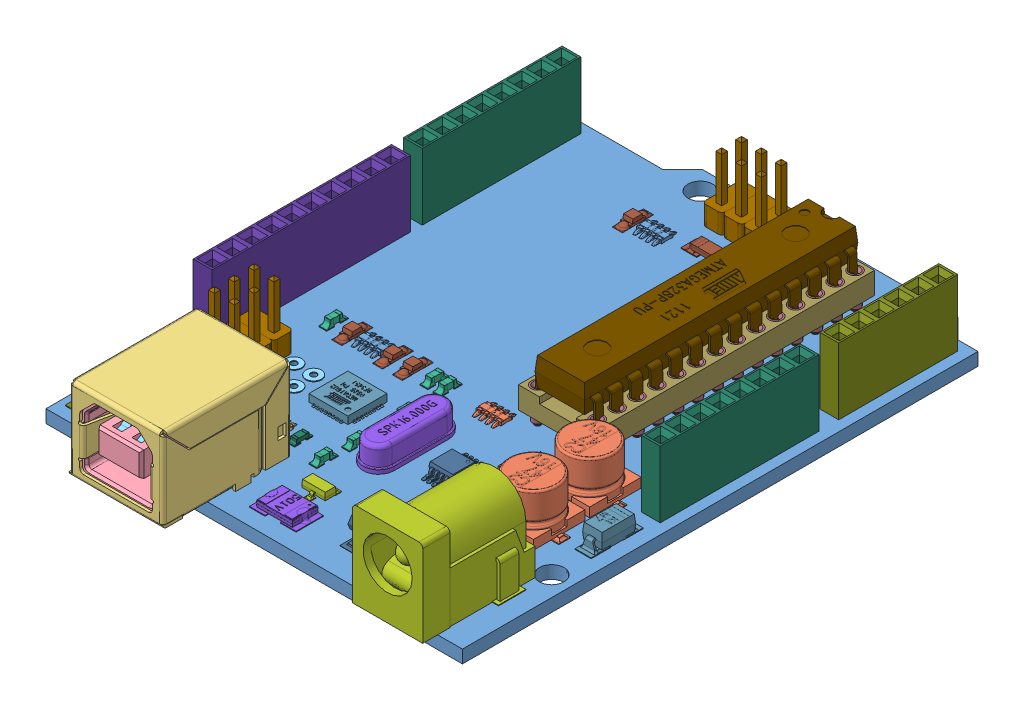
SolidWorks assembly arduino uno, configuration Default. Lengths in mm.
Overall size (53.34 15.25 74.93).
88 component instances, 35 part files, 136 mates.
Components (placement in the parent):
- unoboard blue-1: unoboard blue [Default] at origin size (53.34 1.65 68.58)
- 47uf CAP Dcase-1: 47uf CAP Dcase [Default] at (-9.4141 0 -18.4991) x (0 0 -1) z (1 0 0) size (6.6 5.81 8)
- USB type b-1: USB type b [Default] at (-38.02 0.43 6.35) size (14.34 15.2 16.5)
  - USB SHELL-1: USB SHELL [Default] at origin size (14.34 15.2 16.5)
  - USB core-1: USB core [Default] at origin size (11.3 10.68 15.75)
  - usb top contact-1: usb top contact [Default] at (1.25 6.09 -0.38) size (1 9.67 13.76)
  - usb btm contact-1: usb btm contact [Default] at (1.25 4.41 -0.38) size (1 6.84 11.76)
  - usb btm contact-2: usb btm contact [Default] at (-1.25 4.41 -0.38) size (1 6.84 11.76)
  - usb top contact-2: usb top contact [Default] at (-1.25 6.09 -0.38) size (1 9.67 13.76)
- power jack-1: power jack [Default] at (-7.675 0 1.905) size (11.2 15.2 15.9)
- 47uf CAP Dcase-2: 47uf CAP Dcase [Default] at (-9.4141 0 -25.7132) x (0 0 -1) z (1 0 0) size (6.6 5.81 8)
- crystal-1: crystal [Default] at (-26.162 0 -18.923) x (1 0 0) z (0 0 -1) size (4 5 11)
- 2pin_header__02-1: 2pin_header__02 [Default] at (-46.23 0 -15.75) size (5 11.75 2.54)
- nano - reg-1: nano - reg [Default] at (-17.399 0 -7.747) size (6.5 1.69 8.3)
- led-1: led [Default] at (-34.29 0 -27.94) x (0 0 1) z (-1 0 0) size (4 0.86 1.35)
- 2pin_header__02-2: 2pin_header__02 [Default] at (-30.43 0 -64.91) x (0 0 1) z (-1 0 0) size (5 11.75 2.54)
- dip28-1: dip28 [Default] at (-16.383 1.5 -46.355) x (0 0 -1) z (1 0 0) size (35.48 7.37 10.1)
  - dip28-1: dip28 [Default] at origin size (35.48 2.8 10.1)
  - dip socket pin-1: dip socket pin [Default] at (16.51 2.8 -3.81) size (1.7 7.37 1.7)
  - dip socket pin-2: dip socket pin [Default] at (16.51 2.8 3.81) size (1.7 7.37 1.7)
  - dip socket pin-3: dip socket pin [Default] at (13.97 2.8 -3.81) size (1.7 7.37 1.7)
  - dip socket pin-4: dip socket pin [Default] at (13.97 2.8 3.81) size (1.7 7.37 1.7)
  - dip socket pin-5: dip socket pin [Default] at (11.43 2.8 -3.81) size (1.7 7.37 1.7)
  - dip socket pin-6: dip socket pin [Default] at (11.43 2.8 3.81) size (1.7 7.37 1.7)
  - dip socket pin-7: dip socket pin [Default] at (8.89 2.8 -3.81) size (1.7 7.37 1.7)
  - dip socket pin-8: dip socket pin [Default] at (8.89 2.8 3.81) size (1.7 7.37 1.7)
  - dip socket pin-9: dip socket pin [Default] at (6.35 2.8 -3.81) size (1.7 7.37 1.7)
  - dip socket pin-10: dip socket pin [Default] at (6.35 2.8 3.81) size (1.7 7.37 1.7)
  - dip socket pin-11: dip socket pin [Default] at (3.81 2.8 -3.81) size (1.7 7.37 1.7)
  - dip socket pin-12: dip socket pin [Default] at (3.81 2.8 3.81) size (1.7 7.37 1.7)
  - dip socket pin-13: dip socket pin [Default] at (1.27 2.8 -3.81) size (1.7 7.37 1.7)
  - dip socket pin-14: dip socket pin [Default] at (1.27 2.8 3.81) size (1.7 7.37 1.7)
  - dip socket pin-15: dip socket pin [Default] at (-1.27 2.8 -3.81) size (1.7 7.37 1.7)
  - dip socket pin-16: dip socket pin [Default] at (-1.27 2.8 3.81) size (1.7 7.37 1.7)
  - dip socket pin-17: dip socket pin [Default] at (-3.81 2.8 -3.81) size (1.7 7.37 1.7)
  - dip socket pin-18: dip socket pin [Default] at (-3.81 2.8 3.81) size (1.7 7.37 1.7)
  - dip socket pin-19: dip socket pin [Default] at (-6.35 2.8 -3.81) size (1.7 7.37 1.7)
  - dip socket pin-20: dip socket pin [Default] at (-6.35 2.8 3.81) size (1.7 7.37 1.7)
  - dip socket pin-21: dip socket pin [Default] at (-8.89 2.8 -3.81) size (1.7 7.37 1.7)
  - dip socket pin-22: dip socket pin [Default] at (-8.89 2.8 3.81) size (1.7 7.37 1.7)
  - dip socket pin-23: dip socket pin [Default] at (-11.43 2.8 -3.81) size (1.7 7.37 1.7)
  - dip socket pin-24: dip socket pin [Default] at (-11.43 2.8 3.81) size (1.7 7.37 1.7)
  - dip socket pin-25: dip socket pin [Default] at (-13.97 2.8 -3.81) size (1.7 7.37 1.7)
  - dip socket pin-26: dip socket pin [Default] at (-13.97 2.8 3.81) size (1.7 7.37 1.7)
  - dip socket pin-27: dip socket pin [Default] at (-16.51 2.8 -3.81) size (1.7 7.37 1.7)
  - dip socket pin-28: dip socket pin [Default] at (-16.51 2.8 3.81) size (1.7 7.37 1.7)
- 2pin_header__02-3: 2pin_header__02 [Default] at (-27.89 0 -64.91) x (0 0 1) z (-1 0 0) size (5 11.75 2.54)
- 2pin_header__02-4: 2pin_header__02 [Default] at (-25.35 0 -64.91) x (0 0 1) z (-1 0 0) size (5 11.75 2.54)
- 2pin_header__02-5: 2pin_header__02 [Default] at (-46.23 0 -18.29) size (5 11.75 2.54)
- 2pin_header__02-6: 2pin_header__02 [Default] at (-46.23 0 -20.83) size (5 11.75 2.54)
- atmega16u2-1: atmega16u2 [Default] at (-34.671 0.06 -20) x (1 0 0) z (0 0 -1) size (5.5 1.01 5.5)
- led-2: led [Default] at (-36.83 0 -27.94) x (0 0 1) z (-1 0 0) size (4 0.86 1.35)
- led-3: led [Default] at (-42.037 0 -27.94) x (0 0 1) z (-1 0 0) size (4 0.86 1.35)
- led-4: led [Default] at (-36.576 0 -58.42) x (0 0 1) z (-1 0 0) size (4 0.86 1.35)
- 8 PORT HEADER-3: 8 PORT HEADER [Default] at (-50.8 0 -45.72) x (0 0 -1) z (1 0 0) size (20.32 10.51 2.41)
- 8 PORT HEADER-4: 8 PORT HEADER [Default] at (-2.54 0 -27.94) x (0 0 -1) z (1 0 0) size (20.32 10.51 2.41)
- 6 PORT HEADER-3: 6 PORT HEADER [Default] at (-2.54 0 -50.8) x (0 0 -1) z (1 0 0) size (15.24 10.51 2.41)
- 10 PORT HEADER-1: 10 PORT HEADER [Default] at (-50.8 0 -18.796) x (0 0 -1) z (1 0 0) size (25.4 10.51 2.41)
- ATMEL328P-1: ATMEL328P [Default] at (-16.383 4.3 -46.355) x (0 0 -1) z (1 0 0) size (35 7.27 7.87)
- 102 RESISTOR PACK-1: 102 RESISTOR PACK [Default] at (-33.782 0 -58.42) size (3.2 0.46 3)
- 102 RESISTOR PACK-2: 102 RESISTOR PACK [Default] at (-39.37 0 -27.94) size (3.2 0.46 3)
- 103 RESISTOR PACK-3: 103 RESISTOR PACK [Default] at (-23.876 0 -27.94) size (3.2 0.46 3)
- 220 RESISTOR PACK-1: 220 RESISTOR PACK [Default] at (-36.83 0 -12.827) size (3.2 0.46 3)
- 16mhz crystal - measured-1: 16mhz crystal - measured [Default] at (-24.892 0 -41.275) x (0 0 -1) z (1 0 0) size (3.4 0.8 2)
- PADS001-1: PADS001 [Default] at (-39.878 0.1 -18.288) x (-1 0 0) z (0 0 1) size (4.54 0.1 4.54)
- 603 cap on pad-1: 603 cap on pad [Default] at (-44.45 0 -27.94) x (0 0 -1) z (1 0 0) size (2.76 0.9 1.12)
- ssot3-1: ssot3 [Default] at (-26.5 0 -8.128) x (-1 0 0) z (0 0 -1) size (3 1.13 3.09)
- mf-msmf050-2-1: mf-msmf050-2 [Default] at (-26.5 0 -4.064) size (5.77 1.02 3.72)
- 603 cap on pad-2: 603 cap on pad [Default] at (-29.845 0 -27.94) x (0 0 -1) z (1 0 0) size (2.76 0.9 1.12)
- 603 cap on pad-3: 603 cap on pad [Default] at (-31.496 0 -27.94) x (0 0 -1) z (1 0 0) size (2.76 0.9 1.12)
- lmv358-1: lmv358 [Default] at (-15.24 0 -21.971) x (0 0 -1) z (1 0 0) size (3.7 1.4 2.9)
- 603 cap on pad-4: 603 cap on pad [Default] at (-15.24 0 -18.415) size (2.76 0.9 1.12)
- 603 cap on pad-5: 603 cap on pad [Default] at (-29.845 0 -12.065) x (0 0 1) z (-1 0 0) size (2.76 0.9 1.12)
- 603 cap on pad-6: 603 cap on pad [Default] at (-29.591 0 -22.352) x (0 0 1) z (-1 0 0) size (2.76 0.9 1.12)
- 603 cap on pad-7: 603 cap on pad [Default] at (-29.591 0 -16.002) x (0 0 1) z (-1 0 0) size (2.76 0.9 1.12)
- 603 cap on pad-8: 603 cap on pad [Default] at (-41.91 0 -12.7) x (0 0 1) z (-1 0 0) size (2.76 0.9 1.12)
- lp2985dgkr-1: lp2985dgkr [Default] at (-20.32 0 -19.05) x (0 0 -1) z (1 0 0) size (5.85 1.1 3)
- cd1206 diode-1: cd1206 diode [Default] at (-27.94 0 -59.436) x (0 0 -1) z (1 0 0) size (2.07 0.96 5)
- cd1206 diode-2: cd1206 diode [Default] at (-46.228 0 -13.081) x (0 0 1) z (-1 0 0) size (2.07 0.96 5)
- 603 resistor-1: 603 resistor [Default] at (-29.591 0 -19.05) x (0 0 1) z (-1 0 0) size (2.36 0.61 1.03)
- blm21-1: blm21 [Default] at (-45.085 0 -7.62) x (0 0 -1) z (1 0 0) size (2.76 0.95 1.32)
- m7 diode-1: m7 diode [Default] at (-2.794 0 -21.59) x (0 0 -1) z (1 0 0) size (6.66 2.35 2.5)
- MLC0603-1: MLC0603 [Default] at (-33.655 0 -12.827) x (0 0 -1) z (1 0 0) size (2.36 0.6 1.03)
- MLC0603-2: MLC0603 [Default] at (-39.37 0 -12.827) x (0 0 -1) z (1 0 0) size (2.36 0.6 1.03)
- RESET BUTTON-1: RESET BUTTON [Default] at (-49.403 0 -6.35) size (6.2 3.1 9.6)
  - RESET CORE-1: RESET CORE [Default] at (0 0.1 0) x (-1 0 0) z (0 0 -1) size (6.2 3.1 9.6)
  - RESET-1: RESET [Default] at (0 0.1 0) x (0 0 1) z (-1 0 0) size (7.3 2 6.2)
- 603 cap on pad-9: 603 cap on pad [Default] at (-15.24 0 -25.625) size (2.76 0.9 1.12)
Mates (geometry in assembly coordinates):
- Distance1: distance = 1.905 mm aligned: plane of power jack-1 through (-7.675 0 1.905) normal (0 0 1); plane of unoboard blue-1 through (0 0 0) normal (0 0 1)
- Coincident2: coincident aligned: plane of unoboard blue-1 through (0 0 0) normal (0 1 0); plane of power jack-1 through (-7.675 0 1.905) normal (0 1 0)
- Coincident3: coincident anti-aligned: plane of unoboard blue-1 through (0 0 0) normal (0 1 0); plane of USB type b-1/USB core-1 through (-38.02 0 6.35) normal (0 -1 0)
- Distance2: distance = 6.35 mm aligned: plane of USB type b-1/USB SHELL-1 through (-38.02 0.43 6.35) normal (0 0 1); plane of unoboard blue-1 through (0 0 0) normal (0 0 1)
- Coincident5: coincident aligned: plane of unoboard blue-1 through (0 0 0) normal (0 1 0); plane of 47uf CAP Dcase-1 through (-9.4141 0 -18.4991) normal (0 1 0)
- Parallel1: parallel anti-aligned: plane of unoboard blue-1 through (0 0 0) normal (0 0 1); plane of 47uf CAP Dcase-1 through (-9.4141 0 -18.4991) normal (0 0 -1)
- Coincident7: coincident aligned: plane of 47uf CAP Dcase-1 through (-6.1141 1.5 -15.1991) normal (1 0 0); plane of 47uf CAP Dcase-2 through (-6.1141 1.5 -22.4132) normal (1 0 0)
- Coincident8: coincident anti-aligned: plane of unoboard blue-1 through (0 0 0) normal (0 1 0); plane of 47uf CAP Dcase-2 through (-8.1891 0 -25.7132) normal (0 -1 0)
- Distance3: distance = 3.175 mm aligned: plane of power jack-1 through (-3.175 10.5 -1.595) normal (1 0 0); plane of unoboard blue-1 through (0 -1.65 0) normal (1 0 0)
- Distance4: distance = 32 mm aligned: plane of USB type b-1/USB SHELL-1 through (-32 0.43 6.35) normal (1 0 0); plane of unoboard blue-1 through (0 -1.65 0) normal (1 0 0)
- Coincident11: coincident anti-aligned: plane of unoboard blue-1 through (0 0 0) normal (0 1 0); plane of crystal-1 through (-26.162 0 -22.423) normal (0 -1 0)
- Concentric1: concentric aligned: cylinder of unoboard blue-1 through (-26.162 -10 -16.383) axis (0 1 0) radius 0.5; cylinder of crystal-1 through (-26.162 -2 -16.383) axis (0 1 0) radius 0.4
- Concentric2: concentric aligned: cylinder of unoboard blue-1 through (-26.162 -10 -21.463) axis (0 1 0) radius 0.5; cylinder of crystal-1 through (-26.162 -2 -21.463) axis (0 1 0) radius 0.4
- Coincident12: coincident anti-aligned: plane of unoboard blue-1 through (0 0 0) normal (0 1 0); plane of 2pin_header__02-1 through (-44.23 0 -14.98) normal (0 -1 0)
- Distance5: distance = 15.75 mm aligned: plane of 2pin_header__02-1 through (-46.23 0 -15.75) normal (0 0 1)
- Distance6: distance = 46.23 mm aligned: plane of 2pin_header__02-1 through (-46.23 0 -15.75) normal (1 0 0)
- Coincident15: coincident anti-aligned: plane of unoboard blue-1 through (0 0 0) normal (0 1 0); plane of 2pin_header__02-2 through (-31.2 0 -62.91) normal (0 -1 0)
- Distance7: distance = 64.91 mm aligned: plane of 2pin_header__02-2 through (-30.43 0 -64.91) normal (0 0 1)
- Distance8: distance = 30.43 mm anti-aligned: plane of 2pin_header__02-2 through (-30.43 0 -64.91) normal (-1 0 0)
- Coincident19: coincident anti-aligned: plane of unoboard blue-1 through (0 0 0) normal (0 1 0); plane of nano - reg-1 through (-17.399 0 -7.747) normal (0 -1 0)
- Concentric3: concentric aligned: cylinder of unoboard blue-1 through (-20.193 -10 -62.865) axis (0 1 0) radius 0.4; cylinder of dip28-1/dip socket pin-1 through (-20.193 33.2926 -62.865) axis (0 1 0) radius 0.25
- Concentric4: concentric aligned: cylinder of unoboard blue-1 through (-12.573 -10 -29.845) axis (0 1 0) radius 0.4; cylinder of dip28-1/dip socket pin-28 through (-12.573 33.2926 -29.845) axis (0 1 0) radius 0.25
- Distance9: distance = 1.5 mm anti-aligned: plane of dip28-1/dip28-1 through (-11.333 1.5 -64.095) normal (0 -1 0); plane of unoboard blue-1 through (0 0 0) normal (0 1 0)
- Coincident21: coincident anti-aligned: plane of unoboard blue-1 through (0 0 0) normal (0 1 0); plane of atmega16u2-1 through (-34.671 0 -20) normal (0 -1 0)
- Distance10: distance = 20 mm anti-aligned: plane of atmega16u2-1 through (-34.671 0.06 -20) normal (0 0 -1); plane of unoboard blue-1 through (0 0 0) normal (0 0 1)
- Distance11: distance = 34.671 mm aligned: plane of atmega16u2-1 through (-34.671 0.06 -20) normal (1 0 0); plane of unoboard blue-1 through (0 0 0) normal (1 0 0)
- Coincident25: coincident anti-aligned: plane of unoboard blue-1 through (0 0 0) normal (0 1 0); plane of led-1 through (-34.29 0 -28.94) normal (0 -1 0)
- Distance12: distance = 34.29 mm anti-aligned: plane of led-1 through (-34.29 0 -27.94) normal (-1 0 0); plane of unoboard blue-1 through (0 0 0) normal (1 0 0)
- Distance13: distance = 27.94 mm aligned: plane of led-1 through (-34.29 0 -27.94) normal (0 0 1); plane of unoboard blue-1 through (0 0 0) normal (0 0 1)
- Coincident28: coincident aligned: plane of led-2 through (-36.83 0 -28.94) normal (0 -1 0); plane of led-3 through (-42.037 0 -28.94) normal (0 -1 0)
- Coincident29: coincident aligned: plane of led-1 through (-34.29 0 -27.94) normal (0 0 1); plane of led-2 through (-36.83 0 -27.94) normal (0 0 1)
- Coincident30: coincident aligned: plane of led-1 through (-34.29 0 -27.94) normal (0 0 1); plane of led-3 through (-42.037 0 -27.94) normal (0 0 1)
- Distance14: distance = 2.54 mm aligned: plane of led-2 through (-36.83 0 -27.94) normal (-1 0 0); plane of led-1 through (-34.29 0 -27.94) normal (-1 0 0)
- Coincident32: coincident anti-aligned: plane of unoboard blue-1 through (0 0 0) normal (0 1 0); plane of led-2 through (-36.83 0 -28.94) normal (0 -1 0)
- Distance15: distance = 42.037 mm anti-aligned: plane of led-3 through (-42.037 0 -27.94) normal (-1 0 0); plane of unoboard blue-1 through (0 0 0) normal (1 0 0)
- Coincident34: coincident anti-aligned: plane of unoboard blue-1 through (0 0 0) normal (0 1 0); plane of led-4 through (-36.576 0 -59.42) normal (0 -1 0)
- Distance16: distance = 36.576 mm anti-aligned: plane of led-4 through (-36.576 0 -58.42) normal (-1 0 0); plane of unoboard blue-1 through (0 0 0) normal (1 0 0)
- Distance17: distance = 58.42 mm aligned: plane of led-4 through (-36.576 0 -58.42) normal (0 0 1); plane of unoboard blue-1 through (0 0 0) normal (0 0 1)
- Coincident37: coincident aligned: plane of unoboard blue-1 through (0 0 0) normal (0 1 0); plane of 8 PORT HEADER-4 through (-2.54 0 -27.94) normal (0 1 0)
- Coincident38: coincident aligned: plane of unoboard blue-1 through (0 0 0) normal (0 1 0); plane of 8 PORT HEADER-3 through (-50.8 0 -45.72) normal (0 1 0)
- Parallel2: parallel aligned: plane of unoboard blue-1 through (0 0 0) normal (1 0 0); plane of 8 PORT HEADER-4 through (-2.54 0 -27.94) normal (1 0 0)
- Parallel3: parallel aligned: plane of unoboard blue-1 through (0 0 0) normal (1 0 0); plane of 8 PORT HEADER-3 through (-50.8 0 -45.72) normal (1 0 0)
- Concentric5: concentric aligned: cylinder of unoboard blue-1 through (-2.54 -1.65 -27.94) axis (0 1 0) radius 0.4; line of 8 PORT HEADER-4 through (-2.54 -2.5255 -27.94) axis (0 1 0)
- Concentric6: concentric aligned: cylinder of unoboard blue-1 through (-50.8 -1.65 -45.72) axis (0 1 0) radius 0.4; line of 8 PORT HEADER-3 through (-50.8 -2.5255 -45.72) axis (0 1 0)
- Coincident43: coincident aligned: plane of unoboard blue-1 through (0 0 0) normal (0 1 0); plane of 10 PORT HEADER-1 through (-50.8 0 -18.796) normal (0 1 0)
- Coincident44: coincident aligned: plane of unoboard blue-1 through (0 0 0) normal (0 1 0); plane of 6 PORT HEADER-3 through (-2.54 0 -50.8) normal (0 1 0)
- Parallel4: parallel aligned: plane of unoboard blue-1 through (0 0 0) normal (1 0 0); plane of 6 PORT HEADER-3 through (-2.54 0 -50.8) normal (1 0 0)
- Parallel5: parallel aligned: plane of unoboard blue-1 through (0 0 0) normal (1 0 0); plane of 10 PORT HEADER-1 through (-50.8 0 -18.796) normal (1 0 0)
- Concentric7: concentric aligned: cylinder of unoboard blue-1 through (-50.8 -1.65 -18.796) axis (0 1 0) radius 0.4; line of 10 PORT HEADER-1 through (-50.8 -2.5255 -18.796) axis (0 1 0)
- Concentric9: concentric aligned: cylinder of unoboard blue-1 through (-2.54 -1.65 -50.8) axis (0 1 0) radius 0.4; line of 6 PORT HEADER-3 through (-2.54 -2.5255 -50.8) axis (0 1 0)
- Coincident50: coincident aligned: plane of dip28-1/dip28-1 through (-16.383 1.5 -46.355) normal (0 0 -1); plane of ATMEL328P-1 through (-16.383 4.3 -46.355) normal (0 0 -1)
- Coincident51: coincident aligned: plane of dip28-1 through (-16.383 1.5 -46.355) normal (1 0 0); plane of ATMEL328P-1 through (-16.383 4.3 -46.355) normal (1 0 0)
- Coincident52: coincident aligned: plane of dip28-1/dip28-1 through (-11.333 4.3 -64.095) normal (0 1 0); plane of ATMEL328P-1 through (-16.383 4.3 -46.355) normal (0 1 0)
- Distance18: distance = 7.747 mm: plane of nano - reg-1 through (-17.399 0 -7.747) normal (0 0 1); line of unoboard blue-1 through (0 53.34 -53.34) axis (0 0 1)
- Distance19: distance = 17.399 mm aligned: plane of nano - reg-1 through (-17.399 0 -7.747) normal (1 0 0); plane of unoboard blue-1 through (0 0 0) normal (1 0 0)
- Coincident55: coincident anti-aligned: plane of unoboard blue-1 through (0 0 0) normal (0 1 0); plane of 102 RESISTOR PACK-1 through (-33.982 0 -59.12) normal (0 -1 0)
- Distance20: distance = 33.782 mm aligned: plane of 102 RESISTOR PACK-1 through (-33.782 0 -58.42) normal (1 0 0); plane of unoboard blue-1 through (0 0 0) normal (1 0 0)
- Distance21: distance = 58.42 mm aligned: plane of 102 RESISTOR PACK-1 through (-33.782 0 -58.42) normal (0 0 1); plane of unoboard blue-1 through (0 0 0) normal (0 0 1)
- Coincident58: coincident aligned: plane of 102 RESISTOR PACK-2 through (-39.37 0 -27.94) normal (0 1 0); plane of 103 RESISTOR PACK-3 through (-23.876 0 -27.94) normal (0 1 0)
- Coincident59: coincident aligned: plane of unoboard blue-1 through (0 0 0) normal (0 1 0); plane of 103 RESISTOR PACK-3 through (-23.876 0 -27.94) normal (0 1 0)
- Coincident60: coincident aligned: plane of 102 RESISTOR PACK-2 through (-39.37 0 -27.94) normal (0 0 1); plane of 103 RESISTOR PACK-3 through (-23.876 0 -27.94) normal (0 0 1)
- Distance22: distance = 23.876 mm aligned: plane of 103 RESISTOR PACK-3 through (-23.876 0 -27.94) normal (1 0 0); plane of unoboard blue-1 through (0 0 0) normal (1 0 0)
- Distance23: distance = 39.37 mm aligned: plane of 102 RESISTOR PACK-2 through (-39.37 0 -27.94) normal (1 0 0); plane of unoboard blue-1 through (0 0 0) normal (1 0 0)
- Distance24: distance = 27.94 mm aligned: plane of 102 RESISTOR PACK-2 through (-39.37 0 -27.94) normal (0 0 1); plane of unoboard blue-1 through (0 0 0) normal (0 0 1)
- Distance25: distance = 12.827 mm aligned: plane of 220 RESISTOR PACK-1 through (-36.83 0 -12.827) normal (0 0 1); plane of unoboard blue-1 through (0 0 0) normal (0 0 1)
- Distance26: distance = 36.83 mm aligned: plane of 220 RESISTOR PACK-1 through (-36.83 0 -12.827) normal (1 0 0); plane of unoboard blue-1 through (0 0 0) normal (1 0 0)
- Coincident66: coincident aligned: plane of unoboard blue-1 through (0 0 0) normal (0 1 0); plane of 220 RESISTOR PACK-1 through (-36.83 0 -12.827) normal (0 1 0)
- Coincident67: coincident anti-aligned: plane of unoboard blue-1 through (0 0 0) normal (0 1 0); plane of 16mhz crystal - measured-1 through (-24.892 0 -41.275) normal (0 -1 0)
- Distance27: distance = 41.275 mm anti-aligned: plane of 16mhz crystal - measured-1 through (-24.892 0 -41.275) normal (0 0 -1); plane of unoboard blue-1 through (0 0 0) normal (0 0 1)
- Distance28: distance = 24.892 mm aligned: plane of 16mhz crystal - measured-1 through (-24.892 0 -41.275) normal (1 0 0); plane of unoboard blue-1 through (0 0 0) normal (1 0 0)
- Coincident70: coincident anti-aligned: plane of unoboard blue-1 through (0 0 0) normal (0 1 0); plane of PADS001-1 through (-42.418 0 -18.288) normal (0 -1 0)
- Distance29: distance = 18.288 mm aligned: plane of PADS001-1 through (-39.878 0.1 -18.288) normal (0 0 1); plane of unoboard blue-1 through (0 0 0) normal (0 0 1)
- Distance30: distance = 39.878 mm anti-aligned: plane of PADS001-1 through (-39.878 0.1 -18.288) normal (-1 0 0); plane of unoboard blue-1 through (0 0 0) normal (1 0 0)
- Distance31: distance = 4.064 mm aligned: plane of mf-msmf050-2-1 through (-26.5 0 -4.064) normal (0 0 1); plane of unoboard blue-1 through (0 0 0) normal (0 0 1)
- Distance32: distance = 26.5 mm aligned: plane of mf-msmf050-2-1 through (-26.5 0 -4.064) normal (1 0 0); plane of unoboard blue-1 through (0 0 0) normal (1 0 0)
- Coincident72: coincident aligned: plane of unoboard blue-1 through (0 0 0) normal (0 1 0); plane of mf-msmf050-2-1 through (-26.5 0 -4.064) normal (0 1 0)
- Distance33: distance = 8.128 mm anti-aligned: plane of unoboard blue-1 through (0 0 0) normal (0 0 1); plane of ssot3-1 through (-26.5 0 -8.128) normal (0 0 -1)
- Coincident74: coincident anti-aligned: plane of ssot3-1 through (-26.5 0 -8.128) normal (-1 0 0); plane of mf-msmf050-2-1 through (-26.5 0 -4.064) normal (1 0 0)
- Coincident75: coincident aligned: plane of unoboard blue-1 through (0 0 0) normal (0 1 0); plane of ssot3-1 through (-26.5 0 -8.128) normal (0 1 0)
- Coincident76: coincident anti-aligned: plane of led-1 through (-34.29 0 -27.94) normal (0 0 1); plane of 603 cap on pad-1 through (-44.45 0 -27.94) normal (0 0 -1)
- Coincident77: coincident aligned: plane of unoboard blue-1 through (0 0 0) normal (0 1 0); plane of 603 cap on pad-1 through (-44.45 0 -27.94) normal (0 1 0)
- Distance34: distance = 44.45 mm aligned: plane of 603 cap on pad-1 through (-44.45 0 -27.94) normal (1 0 0); plane of unoboard blue-1 through (0 0 0) normal (1 0 0)
- Coincident79: coincident aligned: plane of 603 cap on pad-2 through (-29.845 0 -27.94) normal (0 1 0); plane of 603 cap on pad-3 through (-31.496 0 -27.94) normal (0 1 0)
- Coincident80: coincident aligned: plane of 603 cap on pad-2 through (-29.845 0 -27.94) normal (0 0 -1); plane of 603 cap on pad-3 through (-31.496 0 -27.94) normal (0 0 -1)
- Coincident81: coincident aligned: plane of unoboard blue-1 through (0 0 0) normal (0 1 0); plane of 603 cap on pad-2 through (-29.845 0 -27.94) normal (0 1 0)
- Coincident82: coincident aligned: plane of 603 cap on pad-1 through (-44.45 0 -27.94) normal (0 0 -1); plane of 603 cap on pad-2 through (-29.845 0 -27.94) normal (0 0 -1)
- Distance36: distance = 29.845 mm aligned: plane of 603 cap on pad-2 through (-29.845 0 -27.94) normal (1 0 0); plane of unoboard blue-1 through (0 0 0) normal (1 0 0)
- Distance37: distance = 31.496 mm aligned: plane of 603 cap on pad-3 through (-31.496 0 -27.94) normal (1 0 0); plane of unoboard blue-1 through (0 0 0) normal (1 0 0)
- Distance38: distance = 15.24 mm aligned: plane of unoboard blue-1 through (0 0 0) normal (1 0 0); plane of lmv358-1 through (-15.24 0 -21.971) normal (1 0 0)
- Distance39: distance = 21.971 mm anti-aligned: plane of lmv358-1 through (-15.24 0 -21.971) normal (0 0 -1); plane of unoboard blue-1 through (0 0 0) normal (0 0 1)
- Coincident88: coincident aligned: plane of unoboard blue-1 through (0 0 0) normal (0 1 0); plane of lmv358-1 through (-15.24 0 -21.971) normal (0 1 0)
- Distance40: distance = 18.415 mm aligned: plane of 603 cap on pad-4 through (-15.24 0 -18.415) normal (0 0 1); plane of unoboard blue-1 through (0 0 0) normal (0 0 1)
- Distance41: distance = 15.24 mm aligned: plane of 603 cap on pad-4 through (-15.24 0 -18.415) normal (1 0 0); plane of unoboard blue-1 through (0 0 0) normal (1 0 0)
- Coincident91: coincident aligned: plane of unoboard blue-1 through (0 0 0) normal (0 1 0); plane of 603 cap on pad-4 through (-15.24 0 -18.415) normal (0 1 0)
- Coincident92: coincident aligned: plane of unoboard blue-1 through (0 0 0) normal (0 1 0); plane of 603 cap on pad-7 through (-29.591 0 -16.002) normal (0 1 0)
- Coincident93: coincident aligned: plane of unoboard blue-1 through (0 0 0) normal (0 1 0); plane of 603 cap on pad-6 through (-29.591 0 -22.352) normal (0 1 0)
- Coincident94: coincident aligned: plane of 603 cap on pad-5 through (-29.845 0 -12.065) normal (0 1 0); plane of unoboard blue-1 through (0 0 0) normal (0 1 0)
- Coincident95: coincident aligned: plane of 603 cap on pad-8 through (-41.91 0 -12.7) normal (0 1 0); plane of unoboard blue-1 through (0 0 0) normal (0 1 0)
- Coincident96: coincident aligned: plane of 603 cap on pad-7 through (-29.591 0 -16.002) normal (-1 0 0); plane of 603 cap on pad-6 through (-29.591 0 -22.352) normal (-1 0 0)
- Distance42: distance = 29.591 mm anti-aligned: plane of 603 cap on pad-7 through (-29.591 0 -16.002) normal (-1 0 0); plane of unoboard blue-1 through (0 0 0) normal (1 0 0)
- Distance43: distance = 22.352 mm: plane of 603 cap on pad-6 through (-29.591 0 -22.352) normal (0 0 1); line of unoboard blue-1 through (0 53.34 -53.34) axis (0 0 1)
- Distance44: distance = 16.002 mm aligned: plane of 603 cap on pad-7 through (-29.591 0 -16.002) normal (0 0 1); plane of unoboard blue-1 through (0 0 0) normal (0 0 1)
- Distance45: distance = 29.845 mm anti-aligned: plane of 603 cap on pad-5 through (-29.845 0 -12.065) normal (-1 0 0); plane of unoboard blue-1 through (0 0 0) normal (1 0 0)
- Distance46: distance = 12.065 mm aligned: plane of 603 cap on pad-5 through (-29.845 0 -12.065) normal (0 0 1); plane of unoboard blue-1 through (0 0 0) normal (0 0 1)
- Distance47: distance = 41.91 mm anti-aligned: plane of 603 cap on pad-8 through (-41.91 0 -12.7) normal (-1 0 0); plane of unoboard blue-1 through (0 0 0) normal (1 0 0)
- Distance48: distance = 12.7 mm aligned: plane of 603 cap on pad-8 through (-41.91 0 -12.7) normal (0 0 1); plane of unoboard blue-1 through (0 0 0) normal (0 0 1)
- Distance49: distance = 20.32 mm aligned: plane of lp2985dgkr-1 through (-20.32 0 -19.05) normal (1 0 0); plane of unoboard blue-1 through (0 0 0) normal (1 0 0)
- Distance50: distance = 19.05 mm anti-aligned: plane of lp2985dgkr-1 through (-20.32 0 -19.05) normal (0 0 -1); plane of unoboard blue-1 through (0 0 0) normal (0 0 1)
- Coincident99: coincident aligned: plane of unoboard blue-1 through (0 0 0) normal (0 1 0); plane of lp2985dgkr-1 through (-20.32 0 -19.05) normal (0 1 0)
- Distance51: distance = 27.94 mm aligned: plane of cd1206 diode-1 through (-27.94 0 -59.436) normal (1 0 0); plane of unoboard blue-1 through (0 0 0) normal (1 0 0)
- Distance52: distance = 59.436 mm anti-aligned: plane of cd1206 diode-1 through (-27.94 0 -59.436) normal (0 0 -1); plane of unoboard blue-1 through (0 0 0) normal (0 0 1)
- Coincident102: coincident aligned: plane of unoboard blue-1 through (0 0 0) normal (0 1 0); plane of cd1206 diode-1 through (-27.94 0 -59.436) normal (0 1 0)
- Distance53: distance = 46.228 mm anti-aligned: plane of cd1206 diode-2 through (-46.228 0 -13.081) normal (-1 0 0); plane of unoboard blue-1 through (0 0 0) normal (1 0 0)
- Distance54: distance = 13.081 mm aligned: plane of unoboard blue-1 through (0 0 0) normal (0 0 1); plane of cd1206 diode-2 through (-46.228 0 -13.081) normal (0 0 1)
- Coincident105: coincident aligned: plane of unoboard blue-1 through (0 0 0) normal (0 1 0); plane of cd1206 diode-2 through (-46.228 0 -13.081) normal (0 1 0)
- Distance55: distance = 29.591 mm anti-aligned: plane of 603 resistor-1 through (-29.591 0 -19.05) normal (-1 0 0); plane of unoboard blue-1 through (0 0 0) normal (1 0 0)
- Distance56: distance = 19.05 mm aligned: plane of 603 resistor-1 through (-29.591 0 -19.05) normal (0 0 1); plane of unoboard blue-1 through (0 0 0) normal (0 0 1)
- Coincident108: coincident aligned: plane of unoboard blue-1 through (0 0 0) normal (0 1 0); plane of 603 resistor-1 through (-29.591 0 -19.05) normal (0 1 0)
- Distance57: distance = 7.62 mm anti-aligned: plane of blm21-1 through (-45.085 0 -7.62) normal (0 0 -1); plane of unoboard blue-1 through (0 0 0) normal (0 0 1)
- Distance58: distance = 45.085 mm aligned: plane of blm21-1 through (-45.085 0 -7.62) normal (1 0 0); plane of unoboard blue-1 through (0 0 0) normal (1 0 0)
- Distance59: distance = 21.59 mm anti-aligned: plane of m7 diode-1 through (-2.794 0 -21.59) normal (0 0 -1); plane of unoboard blue-1 through (0 0 0) normal (0 0 1)
- Distance60: distance = 2.794 mm aligned: plane of m7 diode-1 through (-2.794 0 -21.59) normal (1 0 0); plane of unoboard blue-1 through (0 0 0) normal (1 0 0)
- Coincident113: coincident aligned: plane of unoboard blue-1 through (0 0 0) normal (0 1 0); plane of m7 diode-1 through (-2.794 0 -21.59) normal (0 1 0)
- Coincident114: coincident anti-aligned: plane of 220 RESISTOR PACK-1 through (-36.83 0 -12.827) normal (0 0 1); plane of MLC0603-1 through (-33.655 0 -12.827) normal (0 0 -1)
- Distance61: distance = 33.655 mm aligned: plane of MLC0603-1 through (-33.655 0 -12.827) normal (1 0 0); plane of unoboard blue-1 through (0 0 0) normal (1 0 0)
- Coincident115: coincident aligned: plane of unoboard blue-1 through (0 0 0) normal (0 1 0); plane of MLC0603-1 through (-33.655 0 -12.827) normal (0 1 0)
- Coincident116: coincident aligned: plane of unoboard blue-1 through (0 0 0) normal (0 1 0); plane of blm21-1 through (-45.085 0 -7.62) normal (0 1 0)
- Coincident117: coincident anti-aligned: plane of 220 RESISTOR PACK-1 through (-36.83 0 -12.827) normal (0 0 1); plane of MLC0603-2 through (-39.37 0 -12.827) normal (0 0 -1)
- Coincident118: coincident aligned: plane of unoboard blue-1 through (0 0 0) normal (0 1 0); plane of MLC0603-2 through (-39.37 0 -12.827) normal (0 1 0)
- Distance62: distance = 39.37 mm aligned: plane of MLC0603-2 through (-39.37 0 -12.827) normal (1 0 0); plane of unoboard blue-1 through (0 0 0) normal (1 0 0)
- Distance63: distance = 49.403 mm aligned: plane of RESET BUTTON-1 through (-49.403 0 -6.35) normal (1 0 0); plane of unoboard blue-1 through (0 0 0) normal (1 0 0)
- Distance64: distance = 6.35 mm aligned: plane of RESET BUTTON-1; plane of unoboard blue-1 through (0 0 0) normal (0 0 1)
- Coincident122: coincident aligned: plane of unoboard blue-1 through (0 0 0) normal (0 1 0); plane of RESET BUTTON-1 through (-49.403 0 -6.35) normal (0 1 0)
- Coincident124: coincident anti-aligned: plane of unoboard blue-1 through (0 0 0) normal (0 1 0); plane of 603 cap on pad-9 through (-15.24 0 -25.625) normal (0 -1 0)
- Distance65: distance = 7.21 mm aligned: plane of 603 cap on pad-9 through (-14.84 0.125 -25.245) normal (0 0 1); plane of 603 cap on pad-4 through (-14.84 0.125 -18.035) normal (0 0 1)
- Coincident126: coincident aligned: plane of 603 cap on pad-4 through (-14.44 0.875 -18.79) normal (1 0 0); plane of 603 cap on pad-9 through (-14.44 0.875 -26) normal (1 0 0)
